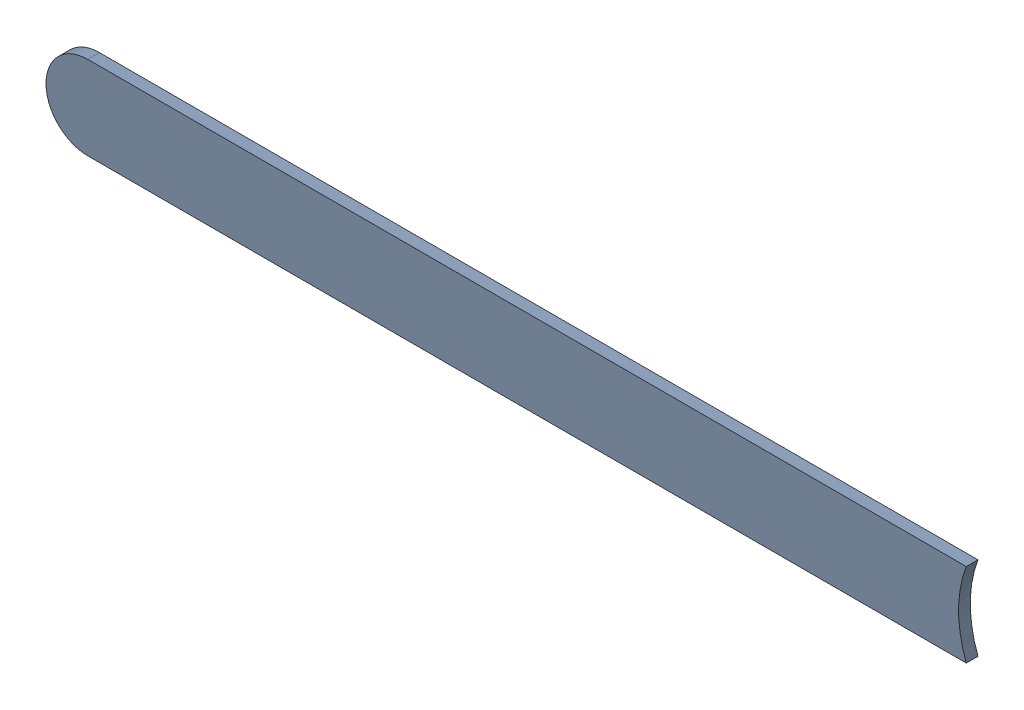
SolidWorks assembly Track (23.098mm,57mm)(26.1mm,57mm) on Top Layer, configuration Predeterminado. Lengths in mm.
Overall size (2.8 0.25 0.04).
2 component instances, 1 part files, 0 mates.
Components (placement in the parent):
- Track (23.098mm,57mm)(26.1mm,57mm) on Top Layer-1-1: Track (23.098mm,57mm)(26.1mm,57mm) on Top Layer-1 [Predeterminado] at (-68.317 -44.187 -0.0457) size (2.8 0.25 0.04)
  - Track (23.098mm,57mm)(26.1mm,57mm) on Top Layer-Part-1-1: Track (23.098mm,57mm)(26.1mm,57mm) on Top Layer-Part-1 [Predeterminado] at origin size (2.8 0.25 0.04)
